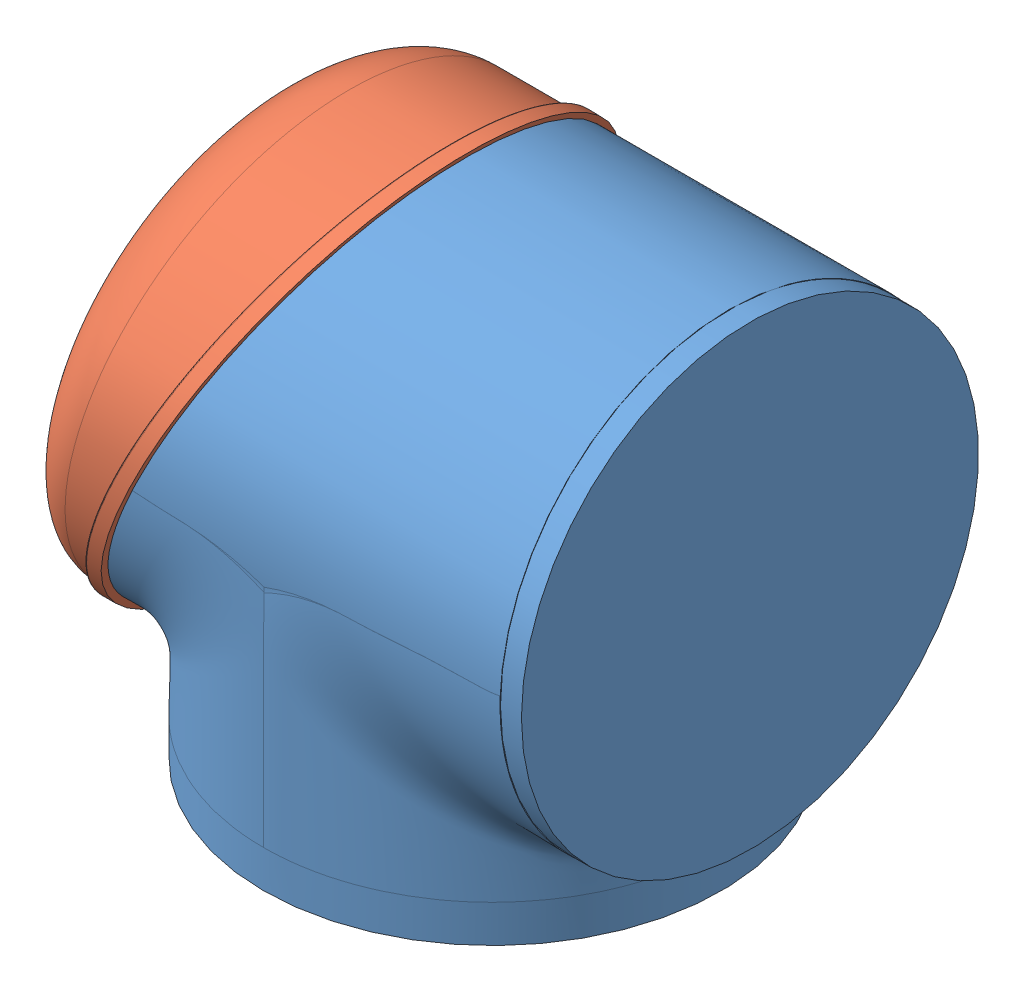
SolidWorks assembly House big, configuration Default. Lengths in mm.
Overall size (133.98 130 124.27).
2 component instances, 2 part files, 2 mates.
Components (placement in the parent):
- Size 3_House_r11_Simple-1: Size 3_House_r11_Simple [Default] at (-14.7699 21.6963 -2.862) size (129.79 128.5 124.27)
- Size 3_Joint lid_r06_Simple-1: Size 3_Joint lid_r06_Simple [Default] at (-14.7702 21.6963 -2.862) size (62.7 119 119.01)
Mates (geometry in assembly coordinates):
- Coincident1: coincident: plane of Size 3_House_r11_Simple-1 through (-42.4531 34.5061 -2.862) normal (-0.907547 0.41995 0); plane of Size 3_Joint lid_r06_Simple-1 through (-18.0963 87.1432 276.6051) normal (0.907547 -0.41995 0)
- Concentric1: concentric aligned: cylinder of Size 3_House_r11_Simple-1 through (175.9221 21.6963 -2.862) axis (-1 0 0) radius 58; cylinder of Size 3_Joint lid_r06_Simple-1 through (-23.2408 13.5355 33.2315) axis (-1 0 0) radius 59.5
